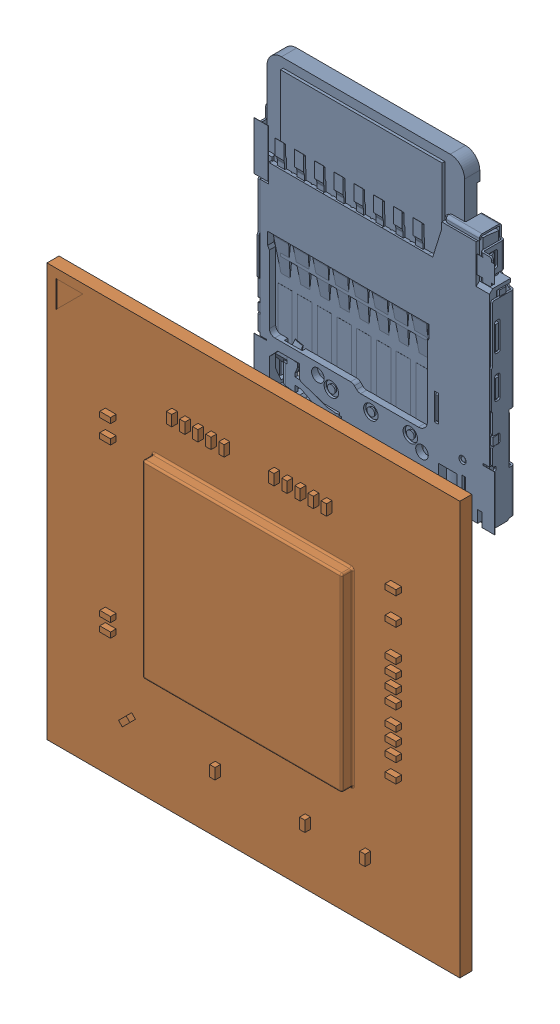
SolidWorks assembly 142-13448-1000-A02_ASM, configuration Default. Lengths in mm.
Overall size (23 37.02 4.04).
2 component instances, 2 part files, 0 mates.
Components (placement in the parent):
- 080-0051-000_3-1: 080-0051-000_3 [Default] at (28.331 29.139 0) x (-1 0 0) z (0 0 -1) size (13.4 17 1.29)
- TM670M-A2_1-1: TM670M-A2_1 [Default] at (23.7 13.45 1.2) size (23 23 1.31)
